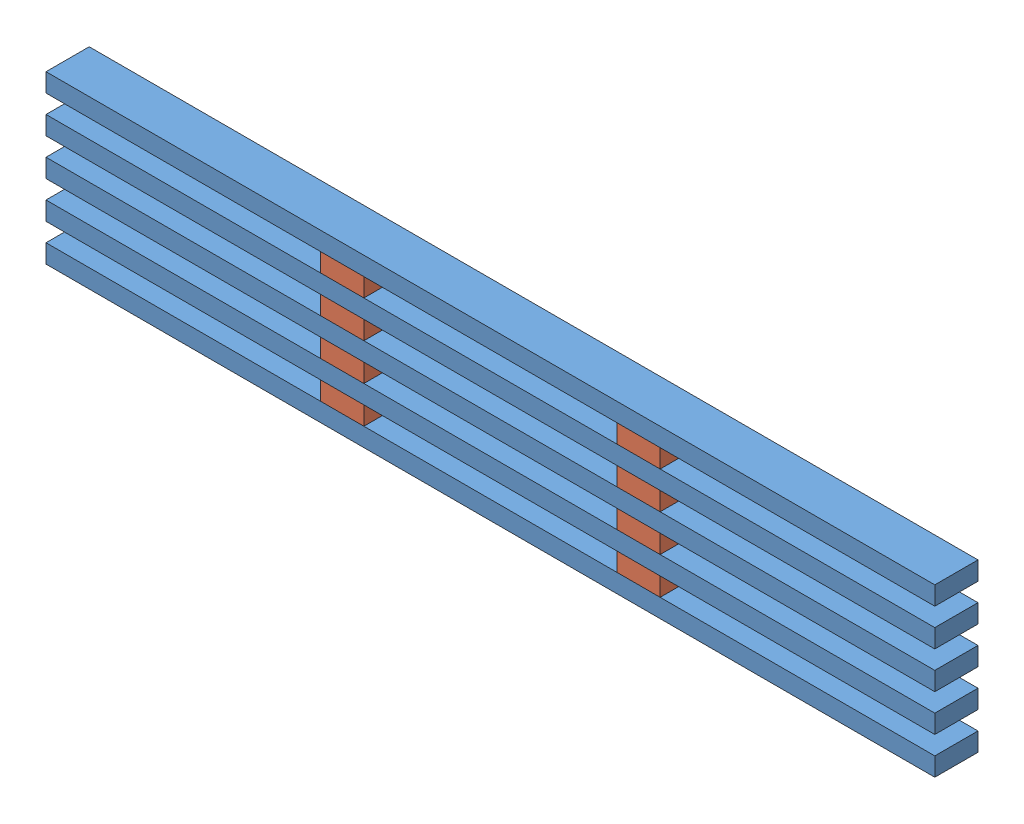
SolidWorks assembly 18x4x6_female_post, configuration Default. Lengths in mm.
Overall size (1828.8 342.9 88.9).
13 component instances, 2 part files, 4 mates.
Components (placement in the parent):
- 2x4x6-1: 2x4x6 [Default] at (-207.2407 1240.9087 1678.6679) size (1828.8 38.1 88.9)
- 2x4x6-2: 2x4x6 [Default] at (-207.2407 1317.1087 1678.6679) size (1828.8 38.1 88.9)
- 2x4x6-3: 2x4x6 [Default] at (-207.2407 1393.3087 1678.6679) size (1828.8 38.1 88.9)
- 2x4x6-4: 2x4x6 [Default] at (-207.2407 1469.5087 1678.6679) size (1828.8 38.1 88.9)
- 2x4x6-5: 2x4x6 [Default] at (-207.2407 1545.7087 1678.6679) size (1828.8 38.1 88.9)
- 4x4x2_gusset-1: 4x4x2_gusset [Default] at (357.9093 1279.0087 1678.6679) size (88.9 38.1 88.9)
- 4x4x2_gusset-2: 4x4x2_gusset [Default] at (967.5093 1279.0087 1678.6679) size (88.9 38.1 88.9)
- 4x4x2_gusset-3: 4x4x2_gusset [Default] at (967.5093 1355.2087 1678.6679) size (88.9 38.1 88.9)
- 4x4x2_gusset-4: 4x4x2_gusset [Default] at (967.5093 1431.4087 1678.6679) size (88.9 38.1 88.9)
- 4x4x2_gusset-5: 4x4x2_gusset [Default] at (967.5093 1507.6087 1678.6679) size (88.9 38.1 88.9)
- 4x4x2_gusset-6: 4x4x2_gusset [Default] at (357.9093 1355.2087 1678.6679) size (88.9 38.1 88.9)
- 4x4x2_gusset-7: 4x4x2_gusset [Default] at (357.9093 1431.4087 1678.6679) size (88.9 38.1 88.9)
- 4x4x2_gusset-8: 4x4x2_gusset [Default] at (357.9093 1507.6087 1678.6679) size (88.9 38.1 88.9)
Mates (geometry in assembly coordinates):
- Coincident1: coincident: point of 2x4x6-1; point of 4x4x2_gusset-1
- Coincident2: coincident: plane of 2x4x6-1 through (-207.2407 1279.0087 1767.5679) normal (0 0 1); plane of 4x4x2_gusset-1 through (357.9093 1317.1087 1767.5679) normal (0 0 1)
- Coincident3: coincident: point of 2x4x6-1; point of 4x4x2_gusset-2
- Coincident4: coincident: plane of 2x4x6-1 through (-207.2407 1279.0087 1767.5679) normal (0 0 1); plane of 4x4x2_gusset-2 through (967.5093 1317.1087 1767.5679) normal (0 0 1)
